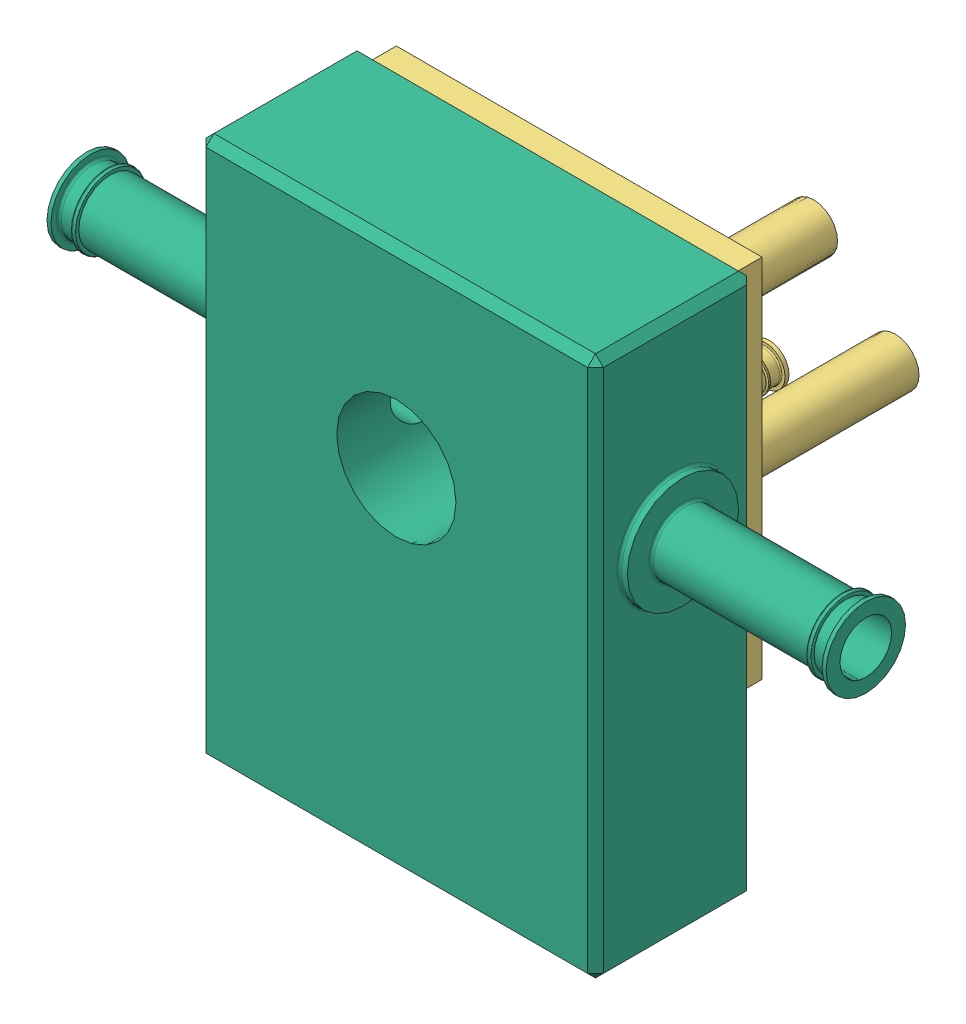
SolidWorks assembly Assieme1, configuration Default. Lengths in mm.
Overall size (98 72 52.5).
6 component instances, 6 part files, 5 mates.
Components (placement in the parent):
- Parte1-2: Parte1 [Default] at (-38.4222 9.9076 15.2962) size (32 32 1.5)
- Parte2-2: Parte2 [Default] at (-38.4222 9.9076 15.2962) size (15 15 0.57)
- Parte3-2: Parte3 [Default] at (-38.4222 9.9076 13.2962) size (56 56 33)
- Parte4-2: Parte4 [Default] at (-38.4222 9.9076 13.2962) size (32 32 0.5)
- Parte5-2: Parte5 [Default] at (-38.4222 9.9076 15.2962) size (32 32 2.5)
- Parte6-2: Parte6 [Default] at (-38.3722 -16.0924 12.7962) size (98 72 20)
Mates (geometry in assembly coordinates):
- Concentrico6: concentric aligned: circle of Parte1-2; circle of Parte2-2
- Coincidente14: coincident aligned: circle of Parte1-2; circle of Parte4-2
- Coincidente15: coincident aligned: circle of Parte3-2; circle of Parte4-2
- Coincidente16: coincident aligned: circle of Parte1-2; circle of Parte5-2
- Coincidente17: coincident anti-aligned: circle of Parte5-2; circle of Parte6-2
